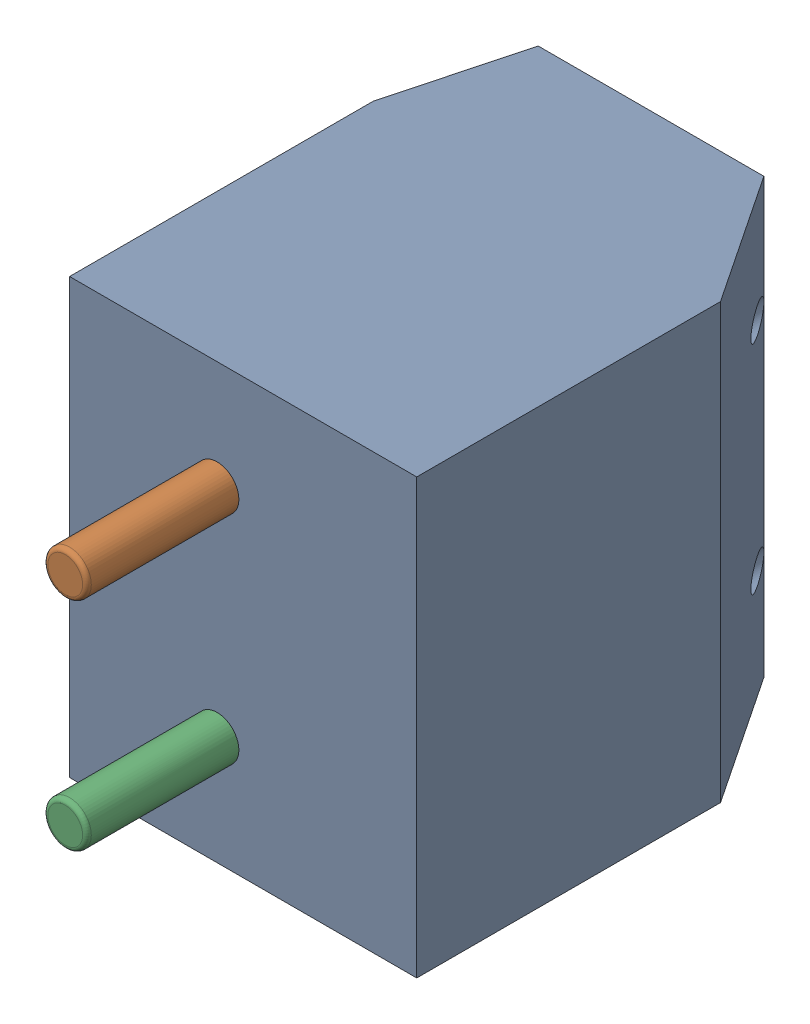
SolidWorks assembly J5, configuration Default. Lengths in mm.
Overall size (8 10 13.5).
4 component instances, 2 part files, 0 mates.
Components (placement in the parent):
- TB2-1: TB2 [Default] at (8.4073 22.3399 -11.7914) x (0 1 0) z (-1 0 0) size (10 13.5 8)
  - User_Library-TB2_TB_case_1-1: User_Library-TB2_TB_case_1 [Default] at (-10 0 0) x (0 0 1) z (0 1 0) size (8 10 10)
  - User_Library-TB2_TB_screw_1-1: User_Library-TB2_TB_screw_1 [Default] at (-2.5 -4.6 4.6) x (-1 0 0) z (0 0 -1) size (3.9 11.9 3.9)
  - User_Library-TB2_TB_screw_1-2: User_Library-TB2_TB_screw_1 [Default] at (-7.5 -4.6 4.6) size (3.9 11.9 3.9)
